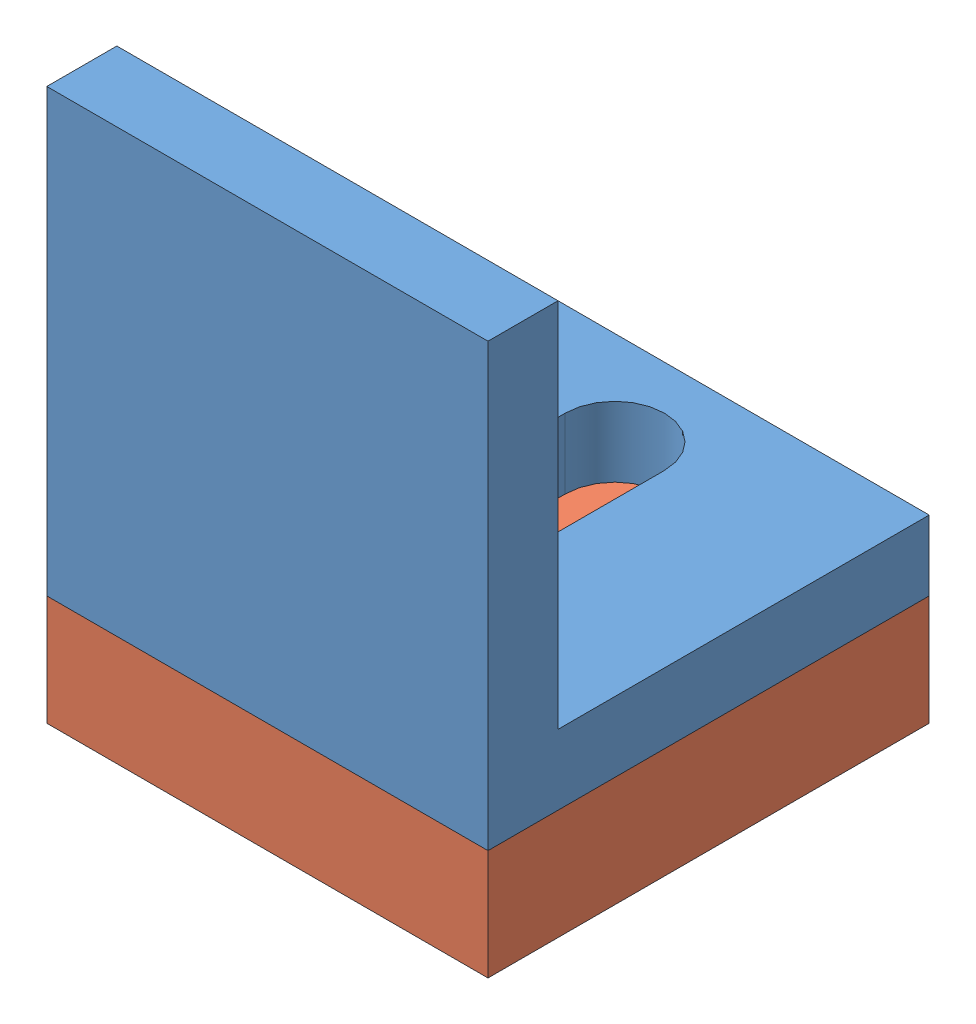
SolidWorks assembly operant box bracket , configuration Default. Lengths in mm.
Overall size (20 25 20).
2 component instances, 2 part files, 4 mates.
Components (placement in the parent):
- operant box_bracket_A-1: operant box_bracket_A [Default] at (-12.8369 -25.9481 -2.8517) size (20 20 20)
- operant box_bracket_B-1: operant box_bracket_B [Default] at (-12.8369 -25.9481 -2.8517) x (-1 0 0) z (0 -1 0) size (20 20 5)
Mates (geometry in assembly coordinates):
- InPlace1: in place: plane of operant box_bracket_A-1 through (7.1631 -25.9481 -2.8517) normal (0 -1 0); plane of ? through (0 -25.9481 0) normal (0 -1 0); moOrthogonalPlaneRef_w of operant box_bracket_A-1 through (7.1631 -25.9481 -2.8517) normal (0 -1 0); plane of ? through (0 -25.9481 0) normal (0 0 -1); plane of operant box_bracket_A-1 through (7.1631 -25.9481 -2.8517) normal (0 -1 0); plane of ? through (0 -25.9481 0) normal (-1 0 0); plane of operant box_bracket_A-1 through (7.1631 -25.9481 -2.8517) normal (0 -1 0); unknown of operant box_bracket_B-1
- Coincident1: coincident aligned: plane of ?; plane of ?
- Coincident2: coincident aligned: moOrthogonalPlaneRef_w of operant box_bracket_A-1 through (-12.8369 -25.9481 -2.8517) normal (0 0 -1); plane of Part3^Assem1-1 through (-12.8369 -25.9481 -2.8517) normal (0 0 -1)
- Coincident3: coincident anti-aligned: moOrthogonalPlaneRef_w of operant box_bracket_A-1 through (-12.8369 -25.9481 -2.8517) normal (1 0 0); plane of Part3^Assem1-1 through (-12.8369 -25.9481 -2.8517) normal (-1 0 0)
